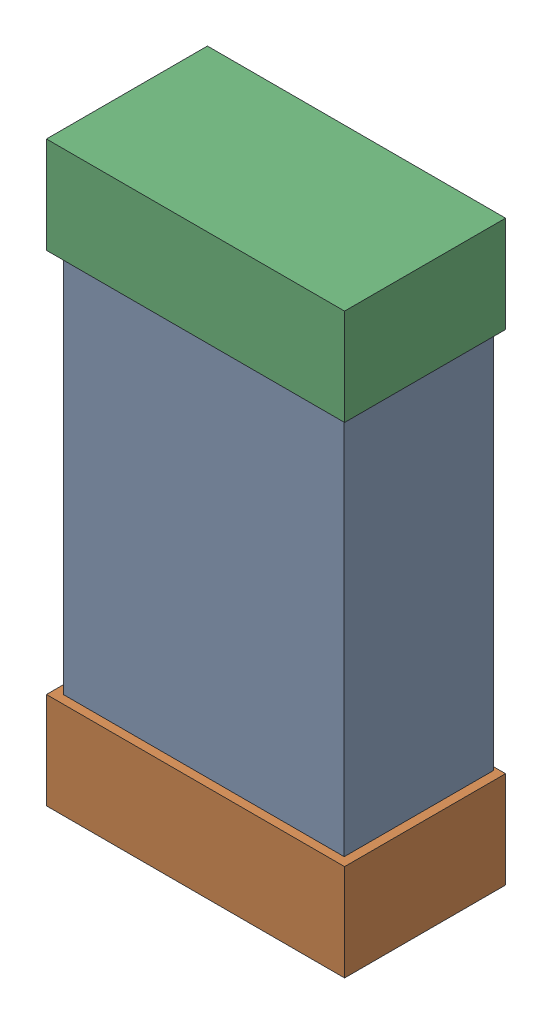
SolidWorks assembly R18, configuration Default. Lengths in mm.
Overall size (0.85 1.65 0.46).
6 component instances, 2 part files, 0 mates.
Components (placement in the parent):
- 432124816_50-1: 432124816_50 [Default] at (30.7 4.4434 -0.8615) size (0.8 1.5 0.42)
  - Extruded (1)-1: Extruded (1) [Default] at origin size (0.8 1.5 0.42)
- 432138512_100-1: 432138512_100 [Default] at (30.7 3.7576 -0.8715) size (0.85 0.28 0.46)
  - Extruded-1: Extruded [Default] at origin size (0.85 0.28 0.46)
- 432138512_101-1: 432138512_101 [Default] at (30.7 5.1291 -0.8715) size (0.85 0.28 0.46)
  - Extruded-1: Extruded [Default] at origin size (0.85 0.28 0.46)
